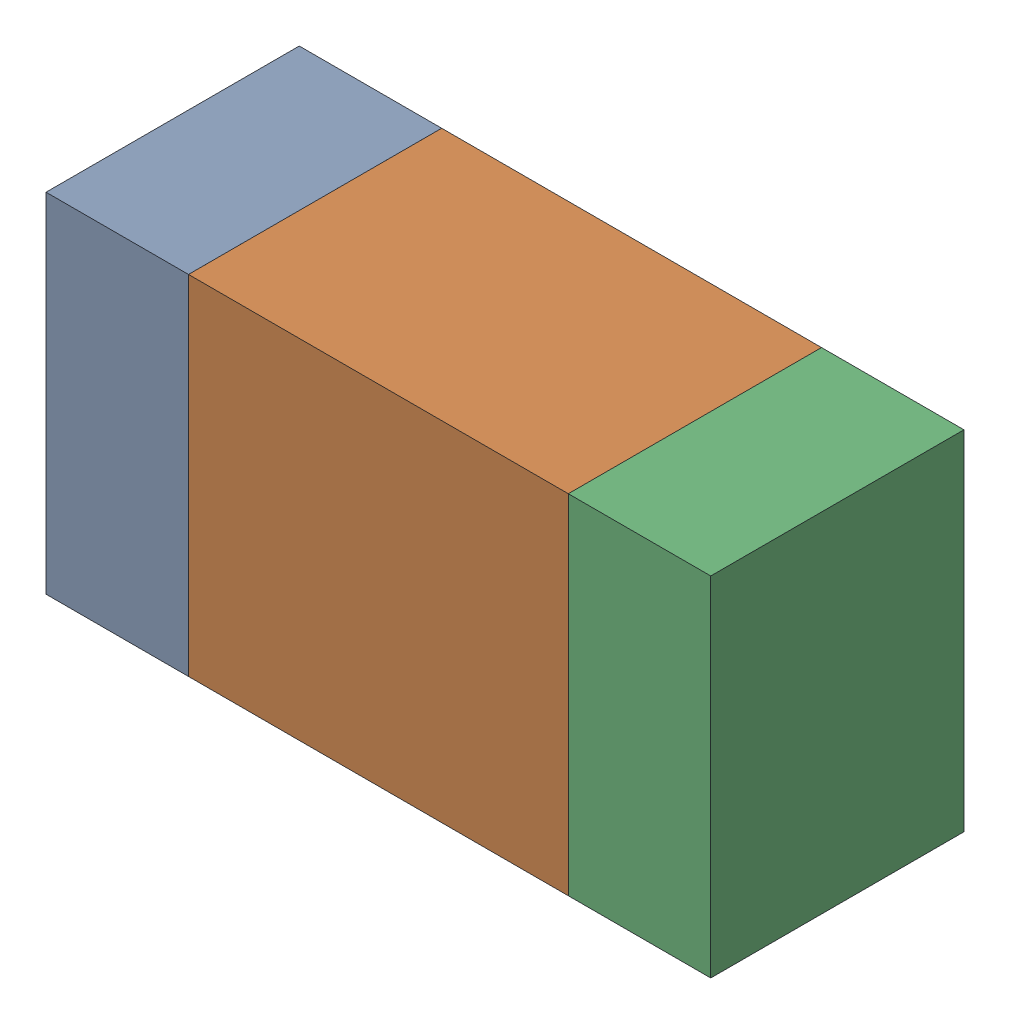
SolidWorks assembly R402PCB, configuration Default. Lengths in mm.
Overall size (1.05 0.55 0.4).
6 component instances, 2 part files, 0 mates.
Components (placement in the parent):
- 854785432-1: 854785432 [Default] at (87.9774 87.7999 0) size (0.22 0.55 0.4)
  - Extruded-1: Extruded [Default] at origin size (0.22 0.55 0.4)
- 854785568-1: 854785568 [Default] at (88.3899 87.7999 0) size (0.6 0.55 0.4)
  - Extruded_2-1: Extruded_2 [Default] at origin size (0.6 0.55 0.4)
- 854785432-2: 854785432 [Default] at (88.8024 87.7999 0) size (0.22 0.55 0.4)
  - Extruded-1: Extruded [Default] at origin size (0.22 0.55 0.4)
